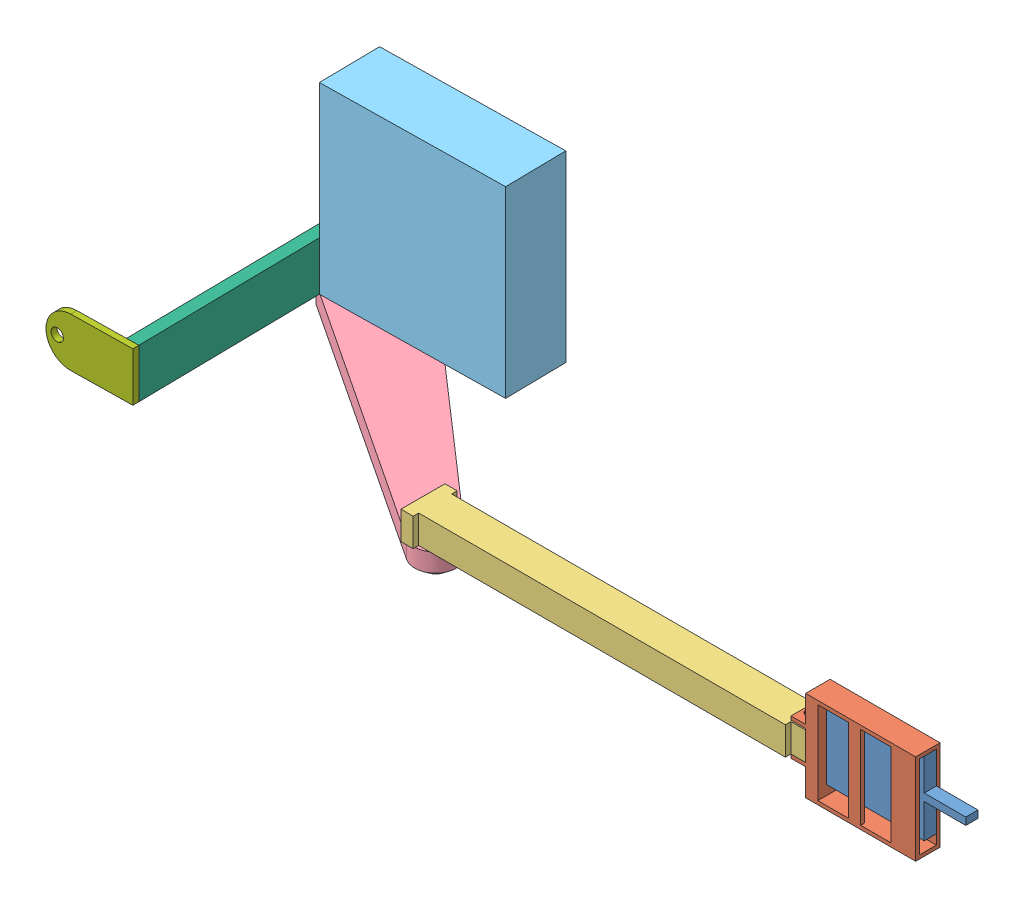
SolidWorks assembly Assem1, configuration Default. Lengths in mm.
Overall size (722.52 180 237.92).
7 component instances, 7 part files, 17 mates.
Components (placement in the parent):
- Part1-2: Part1 [Default] at (105.6491 50.8709 89.7661) size (114.01 60 10)
- Part2-2: Part2 [Default] at (120.0848 45.3423 86.7661) size (102 74 20)
- Part3-3: Part3 [Default] at (-177.9848 56.3423 97.7661) x (1 0 0) z (0 -1 0) size (322 36 43)
- Part4-1: Part4 [Default] at (-493.6814 18.3423 -20.7421) x (0.798268 0 0.602302) z (0 1 0) size (304.24 68.49 15)
- Part5-1: Part5 [Default] at (-479.6609 183.3423 -44.7285) x (0.999877 0 -0.015656) z (0 -1 0) size (150.02 50 180)
- Part6-2: Part6 [Default] at (-554.8665 53.3423 29.8282) x (0.015656 0 0.999877) z (-0.999877 0 0.015656) size (200 40 10)
- Part7-3: Part7 [Default] at (-626.7626 53.3423 125.0195) x (-0.999877 0 0.015656) z (0.015656 0 0.999877) size (70 40 20)
Mates (geometry in assembly coordinates):
- Coincident7: coincident: plane of Part1-2 through (105.6491 50.8709 89.7661) normal (0 0 -1); plane of Part2-2 through (120.0848 45.3423 89.7661) normal (0 0 1)
- Coincident9: coincident: plane of Part1-2 through (-15.1152 50.8709 99.7661) normal (-1 0 0); plane of Part2-2 through (-15.1152 11.3423 89.7661) normal (1 0 0)
- Coincident10: coincident: plane of Part1-2 through (-15.1152 79.3423 99.7661) normal (0 1 0); plane of Part2-2 through (-15.1152 79.3423 89.7661) normal (0 -1 0)
- Coincident15: coincident: plane of Part2-2 through (-37.1152 33.3423 106.7661) normal (0 1 0); plane of Part3-3 through (-177.9848 33.3423 97.7661) normal (0 -1 0)
- Coincident16: coincident: plane of Part2-2 through (-25.1152 45.3423 106.7661) normal (-1 0 0); plane of Part3-3 through (-25.1152 33.3423 106.7661) normal (1 0 0)
- Coincident17: coincident: plane of Part2-2 through (120.0848 45.3423 86.7661) normal (0 0 -1); plane of Part3-3 through (-25.1152 33.3423 86.7661) normal (0 0 -1)
- Concentric1: concentric: cylinder of Part3-3 through (-336.6152 13.3423 97.7661) axis (0 1 0) radius 9.5; cylinder of Part4-1 through (-336.6152 33.3423 97.7661) axis (0 -1 0) radius 10
- Parallel2: parallel: plane of Part3-3 through (-177.9848 33.3423 97.7661) normal (0 -1 0); plane of Part4-1 through (-538.9613 33.3423 -55.5396) normal (0 1 0)
- Coincident20: coincident: plane of Part3-3 through (-177.9848 33.3423 97.7661) normal (0 -1 0); plane of Part4-1 through (-538.9613 33.3423 -55.5396) normal (0 1 0)
- Coincident22: coincident: plane of Part4-1 through (-538.9613 33.3423 -55.5396) normal (0 1 0); plane of Part5-1 through (-479.6609 33.3423 -44.7285) normal (0 -1 0)
- Concentric2: concentric: cylinder of Part4-1 through (-536.1823 33.3423 -52.8094) axis (0 -1 0) radius 20; cylinder of Part5-1 through (-536.1823 3.3423 -52.8094) axis (0 1 0) radius 20
- Coincident23: coincident: plane of Part5-1 through (-555.7424 33.3423 -26.1109) normal (-0.999877 0 0.015656); plane of Part6-2 through (-554.8665 53.3423 29.8282) normal (0.999877 0 -0.015656)
- Coincident24: coincident: plane of Part5-1 through (-556.5252 33.3423 -76.1048) normal (-0.015656 0 -0.999877); plane of Part6-2 through (-566.524 53.3423 -75.9482) normal (-0.015656 0 -0.999877)
- Coincident25: coincident: plane of Part4-1 through (-538.9613 33.3423 -55.5396) normal (0 1 0); plane of Part6-2 through (-563.3929 33.3423 124.0273) normal (0 -1 0)
- Coincident30: coincident: circle of Part6-2; plane of Part7-3 through (-558.6283 53.3423 108.9509) normal (-0.015656 0 -0.999877)
- Coincident31: coincident: plane of Part6-2 through (-554.8665 53.3423 29.8282) normal (0.999877 0 -0.015656); plane of Part7-3 through (-553.3158 53.3423 128.8701) normal (0.999877 0 -0.015656)
- Coincident32: coincident: line of Part6-2 through (-556.5252 33.3423 -76.1048) axis (0.015656 0 0.999877); plane of Part7-3 through (-553.3158 33.3423 128.8701) normal (0 -1 0)
